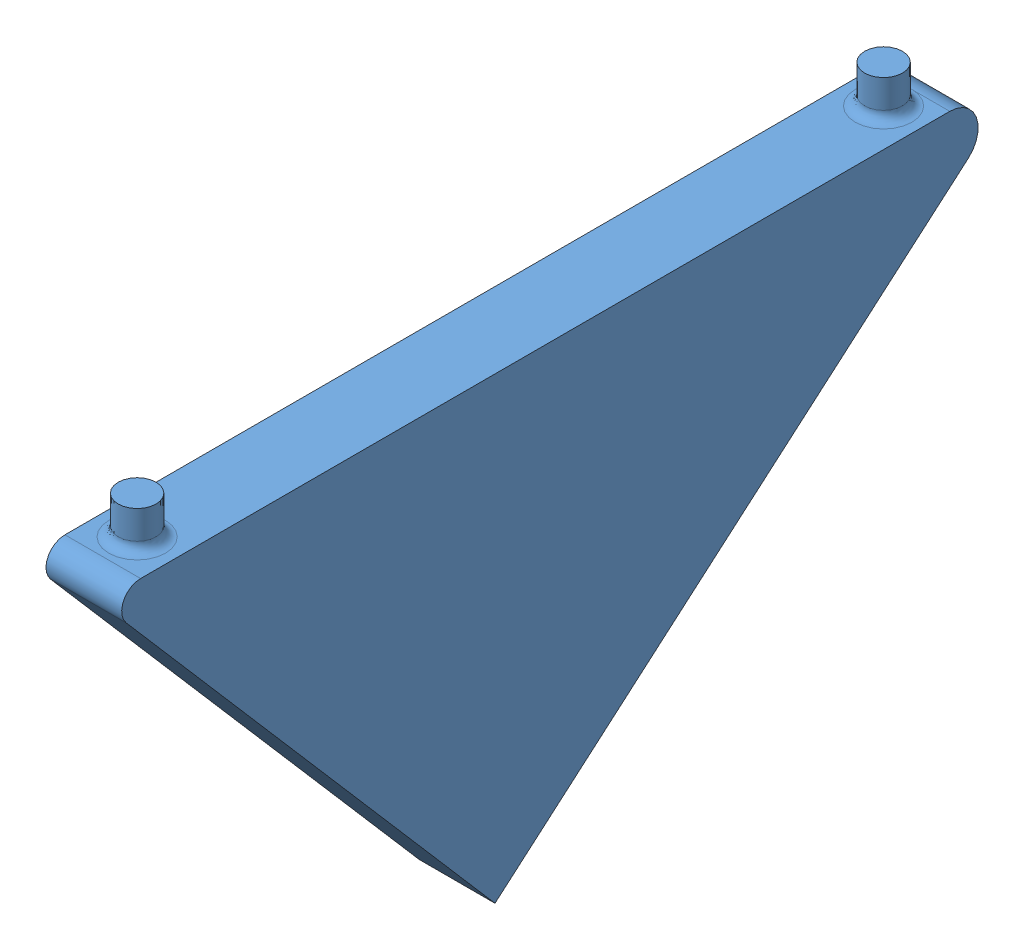
SolidWorks assembly Makita Stand, configuration Default. Lengths in mm.
Overall size (169.54 83.26 147.45).
2 component instances, 2 part files, 4 mates.
Components (placement in the parent):
- Part1^Makita Stand-1: Part1^Makita Stand [Default] at origin size (12.7 83.26 147.45) (virtual)
- Part2^Makita Stand-1: Part2^Makita Stand [Default] x (0 0 -1) z (1 0 0) (virtual)
Mates (geometry in assembly coordinates):
- InPlace1: in place: plane of Part2^Makita Stand-1 through (0 0 0) normal (1 0 0); moOrthogonalPlaneRef_w of Part2^Makita Stand-1 through (0 0 0) normal (0 1 0); plane of Part2^Makita Stand-1 through (0 0 0) normal (0 0 -1); unknown of Part2^Makita Stand-1
- Coincident1: coincident aligned: 
- Coincident2: coincident aligned: plane of Part2^Assem1-1 through (0 0 0) normal (0 1 0)
- Coincident3: coincident anti-aligned: plane of Part2^Assem1-1 through (0 0 0) normal (0 0 -1)
